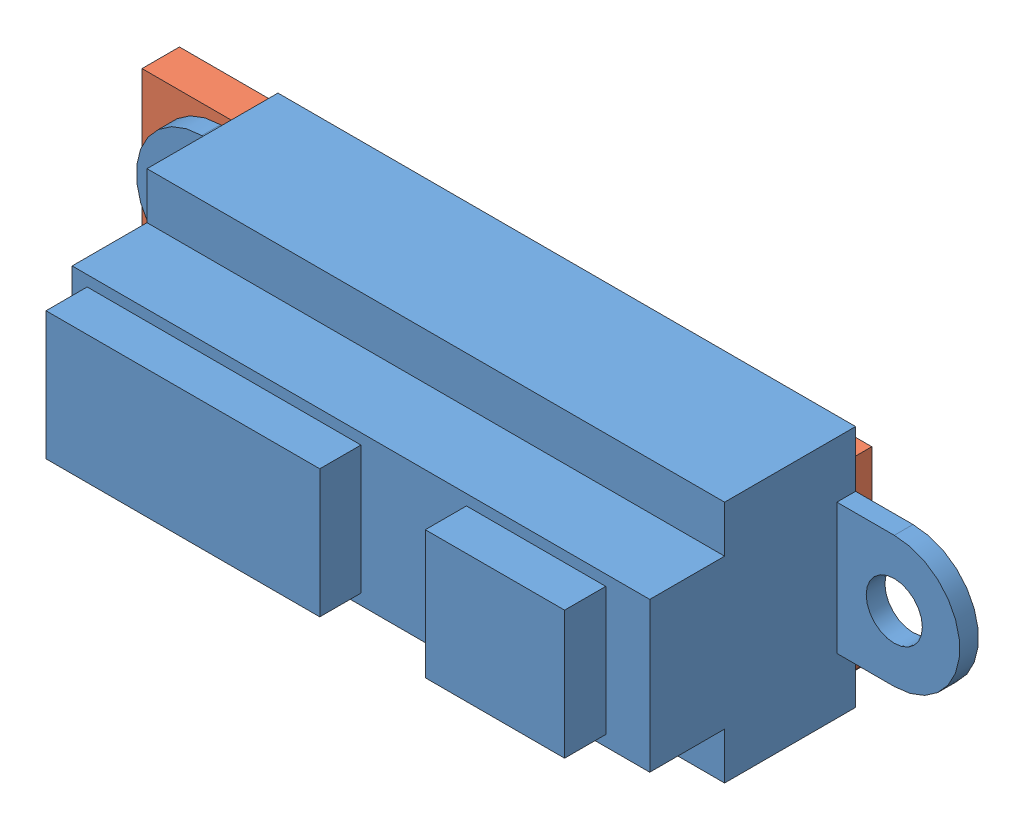
SolidWorks assembly 红外固定部分_下侧装配, configuration 右侧. Lengths in mm.
Overall size (44.7 13 23.2).
2 component instances, 2 part files, 3 mates.
Components (placement in the parent):
- 红外传感器-1: 红外传感器 [默认] at origin size (44 13 13.2)
- 011红外传感器下侧支架2.0-1: 011红外传感器下侧支架2.0 [右侧] at (-0.2 11.5 0) x (-1 0 0) z (0 0 -1) size (37 10.5 10)
Mates (geometry in assembly coordinates):
- 重合5: coincident anti-aligned: plane of 红外传感器-1 through (0 0 0) normal (0 0 -1); plane of 011红外传感器下侧支架2.0-1 through (-0.2 11.5 0) normal (0 0 1)
- 平行1: parallel aligned: plane of 红外传感器-1 through (-15.4335 -6.5 7) normal (0 -1 0); plane of 011红外传感器下侧支架2.0-1 through (22.3 -6.5 -2) normal (0 -1 0)
- 距离2: distance = 3 mm aligned: plane of 红外传感器-1 through (-18.5 -3.5 1) normal (0 -1 0); plane of 011红外传感器下侧支架2.0-1 through (22.3 -6.5 -2) normal (0 -1 0)
